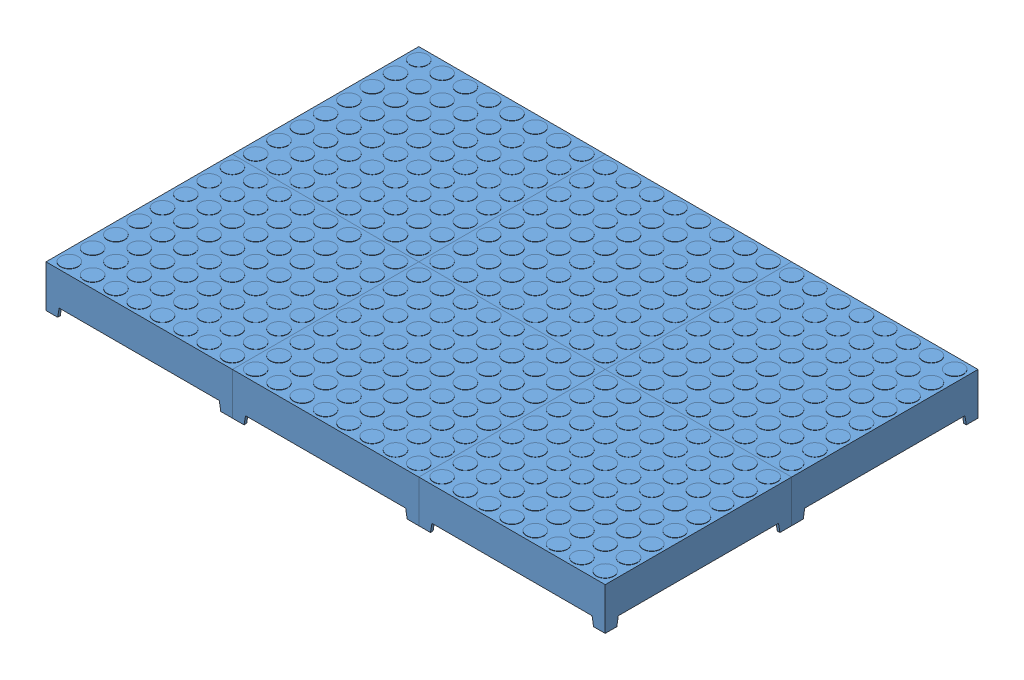
SolidWorks assembly LEDs_face_mount, configuration Valor predeterminado. Lengths in mm.
Overall size (96 9.3 64).
6 component instances, 1 part files, 16 mates.
Components (placement in the parent):
- LED_Matrix-1: LED_Matrix [Valor predeterminado] at (0 -1.5 -16) size (32 9.3 32)
- LED_Matrix-2: LED_Matrix [Valor predeterminado] at (32 -1.5 -16) size (32 9.3 32)
- LED_Matrix-3: LED_Matrix [Valor predeterminado] at (-32 -1.5 -16) size (32 9.3 32)
- LED_Matrix-4: LED_Matrix [Valor predeterminado] at (-32 -1.5 16) size (32 9.3 32)
- LED_Matrix-5: LED_Matrix [Valor predeterminado] at (32 -1.5 16) size (32 9.3 32)
- LED_Matrix-6: LED_Matrix [Valor predeterminado] at (0 -1.5 16) size (32 9.3 32)
Mates (geometry in assembly coordinates):
- Coincidente1: coincident: plane of ? through (12.5788 2.867 38.6258) normal (1 0 0); plane of ? through (12.5788 2.867 6.6258) normal (-1 0 0)
- Coincidente4: coincident: point of ?; unknown of ?
- Coincidente5: coincident: unknown of ?; unknown of ?
- Coincidente6: coincident: plane of ? through (-19.4212 2.867 6.6258) normal (-1 0 0); plane of ? through (-19.4212 2.867 38.6258) normal (1 0 0)
- Coincidente7: coincident: unknown of ?; unknown of ?
- Coincidente9: coincident: unknown of ?; unknown of ?
- Coincidente10: coincident: plane of ? through (-19.4212 2.867 70.6258) normal (1 0 0); plane of ? through (0.0308 -3.5 30.8653) normal (-1 0 0)
- Coincidente11: coincident: unknown of ?; unknown of ?
- Coincidente12: coincident: unknown of ?; unknown of ?
- Coincidente13: coincident: plane of ? through (12.5788 2.867 38.6258) normal (-1 0 0); plane of ? through (32.0308 -3.5 62.8653) normal (1 0 0)
- Coincidente14: coincident: unknown of ?; unknown of ?
- Coincidente15: coincident: unknown of ?; unknown of ?
- Coincidente16: coincident: unknown of ?; unknown of ?
- Coincidente17: coincident: unknown of ?; unknown of ?
- Coincidente19: coincident: unknown of ?; unknown of ?
- Coincidente21: coordinate: point of assembly; moEndPointRef_w of LED_Matrix-6; point of assembly
